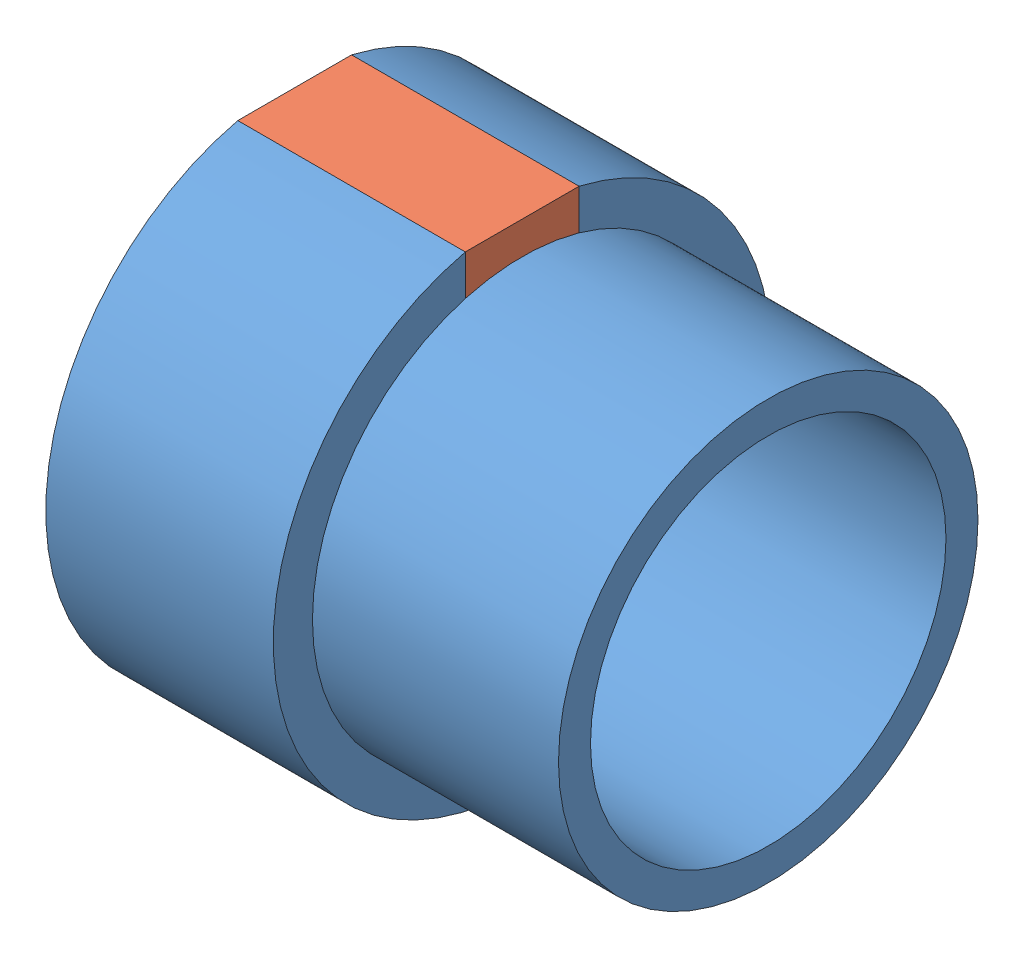
SolidWorks assembly ТП.002.06.01.01.00 - Втулка со шпонкой приводного шкива, configuration 00. Lengths in mm.
Overall size (33.3 34.54 35).
2 component instances, 2 part files, 6 mates.
Components (placement in the parent):
- ТП.002.06.01.01.01 - Втулка приводного шкива-1: ТП.002.06.01.01.01 - Втулка приводного шкива [--] at (149.35 155.8076 0) size (33.3 34.54 35)
- ТП.002.06.01.01.02 - Шпонка 8х8х16-1: ТП.002.06.01.01.02 - Шпонка 8х8х16 [--] at (149.35 155.8076 0) size (16 8.54 8)
Mates (geometry in assembly coordinates):
- Параллельность1: parallel: plane of ТП.002.06.01.01.01 - Втулка приводного шкива-1 through (28.0416 17.0367 -4) normal (0 0 1); plane of assembly through (0 0 0) normal (0 0 1)
- Совпадение1: coincident: plane of ТП.002.06.01.01.01 - Втулка приводного шкива-1 through (0 12.5 0) normal (-1 0 0); plane of assembly through (0 0 0) normal (1 0 0)
- Концентричный1: concentric: cylinder of ? through (26.7474 0 0) axis (1 0 0) radius 12.5
- Совпадение3: coincident: plane of ТП.002.06.01.01.01 - Втулка приводного шкива-1 through (16 17.5 0) normal (1 0 0); plane of ТП.002.06.01.01.02 - Шпонка 8х8х16-1 through (16 0 0) normal (1 0 0)
- Совпадение4: coincident: plane of ТП.002.06.01.01.01 - Втулка приводного шкива-1 through (28.0416 17.0367 -4) normal (0 0 1); plane of ТП.002.06.01.01.02 - Шпонка 8х8х16-1 through (27.6994 17.0367 -4) normal (0 0 -1)
- Расстояние1: distance = 4 mm: plane of ТП.002.06.01.01.02 - Шпонка 8х8х16-1 through (27.6994 8.5 4) normal (0 -1 0); cylinder of ТП.002.06.01.01.01 - Втулка приводного шкива-1 through (26.7474 0 0) axis (1 0 0) radius 12.5
